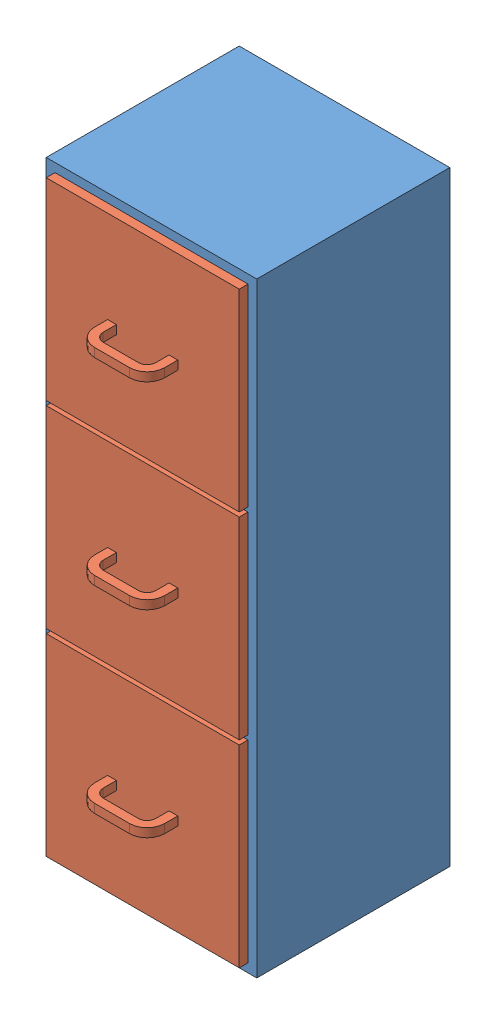
SolidWorks assembly S1_E3_INT_E, configuration Predeterminado. Lengths in mm.
Overall size (48 138 53).
4 component instances, 2 part files, 9 mates.
Components (placement in the parent):
- S1_E3_INT_P2-1: S1_E3_INT_P2 [Predeterminado] at (-101.7476 -88.57 138) size (48 138 44)
- S1_E3_INT_P1-1: S1_E3_INT_P1 [Predeterminado] at (-97.7476 5.43 142) size (44 44 49)
- S1_E3_INT_P1-2: S1_E3_INT_P1 [Predeterminado] at (-97.7476 -39.57 142) size (44 44 49)
- S1_E3_INT_P1-3: S1_E3_INT_P1 [Predeterminado] at (-97.7476 -84.57 142) size (44 44 49)
Mates (geometry in assembly coordinates):
- Coincidente1: coincident anti-aligned: plane of S1_E3_INT_P2-1 through (-97.7476 5.43 182) normal (0 1 0); plane of S1_E3_INT_P1-1 through (-97.7476 5.43 182) normal (0 -1 0)
- Ancho3: width aligned: plane of S1_E3_INT_P2-1 through (-97.7476 -88.57 182) normal (1 0 0); plane of S1_E3_INT_P2-1 through (-57.7476 -88.57 182) normal (-1 0 0); plane of S1_E3_INT_P1-1 through (-57.7476 5.43 182) normal (1 0 0); plane of S1_E3_INT_P1-1 through (-97.7476 5.43 182) normal (-1 0 0)
- Distancia límite1: limit distance = 0 mm anti-aligned: plane of S1_E3_INT_P2-1 through (-101.7476 -88.57 142) normal (0 0 1); plane of S1_E3_INT_P1-1 through (-97.7476 5.43 142) normal (0 0 -1)
- Coincidente2: coincident anti-aligned: plane of S1_E3_INT_P2-1 through (-97.7476 -39.57 182) normal (0 1 0); plane of S1_E3_INT_P1-2 through (-97.7476 -39.57 182) normal (0 -1 0)
- Distancia límite2: limit distance = 0 mm anti-aligned: plane of S1_E3_INT_P2-1 through (-101.7476 -88.57 142) normal (0 0 1); plane of S1_E3_INT_P1-2 through (-97.7476 -39.57 142) normal (0 0 -1)
- Coincidente3: coincident anti-aligned: plane of S1_E3_INT_P2-1 through (-101.7476 -84.57 182) normal (0 1 0); plane of S1_E3_INT_P1-3 through (-97.7476 -84.57 182) normal (0 -1 0)
- Distancia límite3: limit distance = 0 mm anti-aligned: plane of S1_E3_INT_P2-1 through (-101.7476 -88.57 142) normal (0 0 1); plane of S1_E3_INT_P1-3 through (-97.7476 -84.57 142) normal (0 0 -1)
- Ancho4: width anti-aligned: plane of S1_E3_INT_P1-2 through (-57.7476 -39.57 182) normal (1 0 0); plane of S1_E3_INT_P1-2 through (-97.7476 -39.57 182) normal (-1 0 0); plane of S1_E3_INT_P2-1 through (-57.7476 -88.57 182) normal (-1 0 0); plane of S1_E3_INT_P2-1 through (-97.7476 -88.57 182) normal (1 0 0)
- Ancho5: width anti-aligned: plane of S1_E3_INT_P2-1 through (-97.7476 -88.57 182) normal (1 0 0); plane of S1_E3_INT_P2-1 through (-57.7476 -88.57 182) normal (-1 0 0); plane of S1_E3_INT_P1-3 through (-97.7476 -84.57 182) normal (-1 0 0); plane of S1_E3_INT_P1-3 through (-57.7476 -84.57 182) normal (1 0 0)
